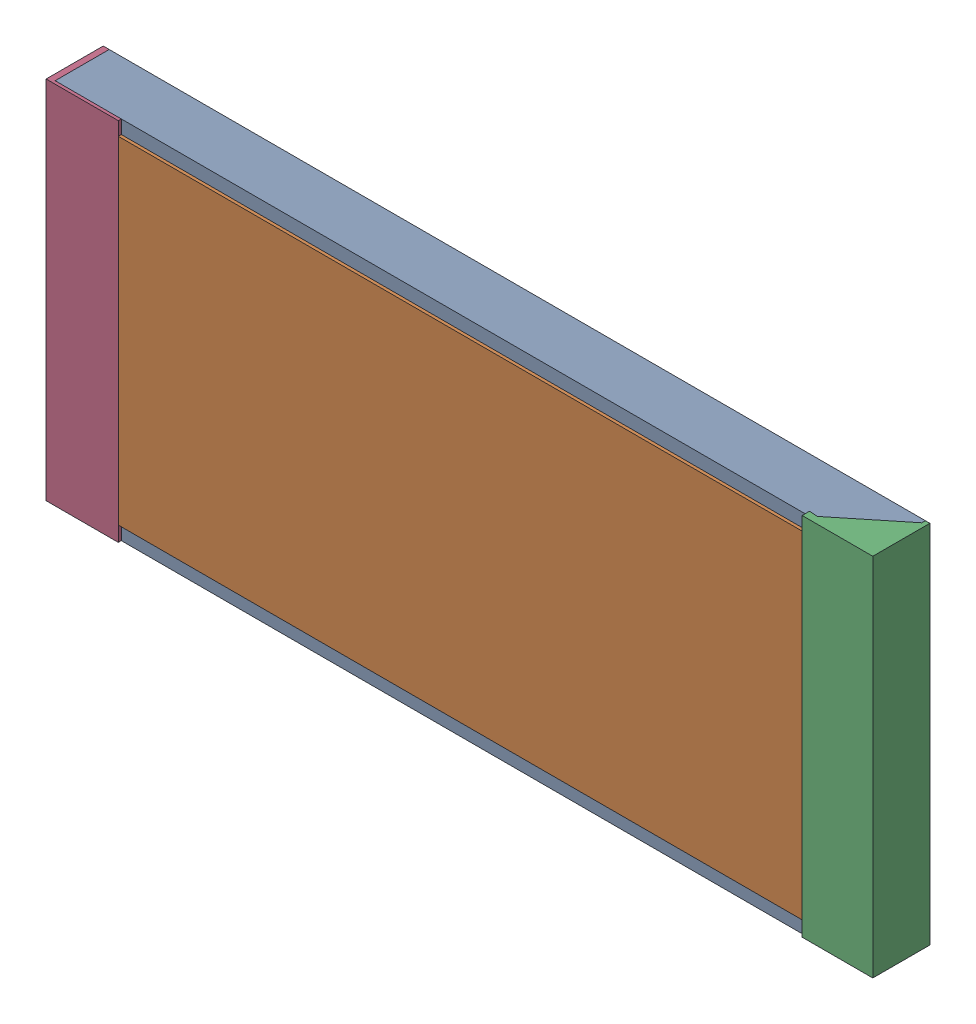
SolidWorks assembly R3, configuration Default. Lengths in mm.
Overall size (6.99 3.09 0.48).
8 component instances, 4 part files, 0 mates.
Components (placement in the parent):
- 577141712-1: 577141712 [Default] at (108.135 194.2764 0) size (6.9 3.09 0.46)
  - Extruded_41-1: Extruded_41 [Default] at origin size (6.9 3.09 0.46)
- 577141840-1: 577141840 [Default] at (108.135 194.2827 0.4572) size (5.78 2.84 0.03)
  - Extruded_42-1: Extruded_42 [Default] at origin size (5.78 2.84 0.03)
- 577141968-1: 577141968 [Default] at (111.3228 194.2764 0) size (0.6 3.09 0.48)
  - Extruded_43-1: Extruded_43 [Default] at origin size (0.6 3.09 0.48)
- 477873424-1: 477873424 [Default] at (104.941 194.2764 0) size (0.61 3.09 0.48)
  - Extruded_44-1: Extruded_44 [Default] at origin size (0.61 3.09 0.48)
